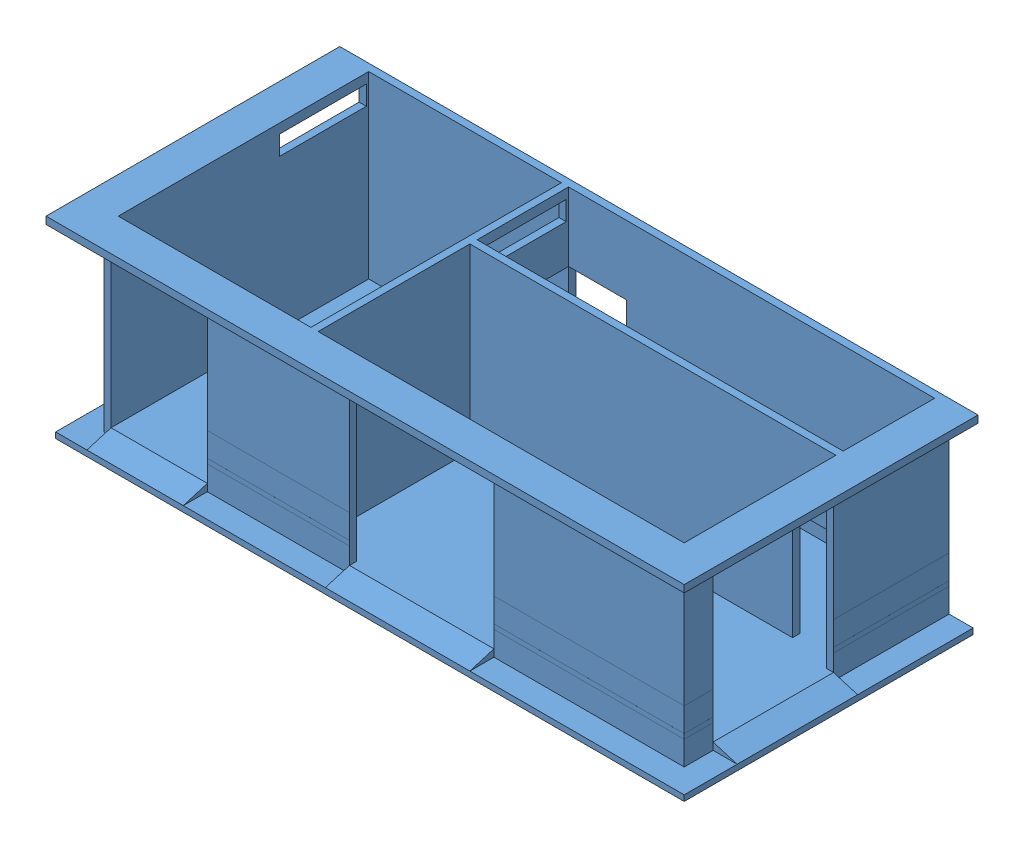
SolidWorks assembly Ensamblaje electricidad del cuarto, configuration Predeterminado. Lengths in mm.
Overall size (13250 4000 6100).
4 component instances, 4 part files, 9 mates.
Components (placement in the parent):
- Cuarto 3-10-18-1: Cuarto 3-10-18 [Predeterminado] at (9927.4307 8626.0275 5841.1732) size (13250 4000 6100)
- trafo de 50 kva-1: trafo de 50 kva [Predeterminado] at (6977.4307 6761.0275 7541.1732) x (1 0 0) z (0 1 0) size (900 600 801)
- tablero de distribuacion de 50 kva-1: tablero de distribuacion de 50 kva [Predeterminado] at (6377.4307 8661.0275 7391.1732) x (0 0 -1) z (-1 0 0) size (600 800 250)
- conexi trafo 50 kva-1: conexi trafo 50 kva [Predeterminado] at (6477.4307 7337.5055 7661.8509) x (0 0 -1) z (1 0 0) size (365.4 1012.7 313.7)
Mates (geometry in assembly coordinates):
- Coincidente1: coincident anti-aligned: plane of Cuarto 3-10-18-1 through (9927.4307 6761.0275 5841.1732) normal (0 1 0); plane of trafo de 50 kva-1 through (6977.4307 6761.0275 7541.1732) normal (0 -1 0)
- Distancia1: distance = 50 mm anti-aligned: plane of Cuarto 3-10-18-1 through (6127.4307 17612.5076 7891.1732) normal (0 0 -1); plane of trafo de 50 kva-1 through (6577.4307 7561.0275 7841.1732) normal (0 0 1)
- Coincidente3: coincident anti-aligned: plane of Cuarto 3-10-18-1 through (6127.4307 10011.0275 5991.1732) normal (1 0 0); plane of tablero de distribuacion de 50 kva-1 through (6127.4307 8661.0275 7391.1732) normal (-1 0 0)
- Distancia2: distance = 200 mm anti-aligned: plane of Cuarto 3-10-18-1 through (6127.4307 17612.5076 7891.1732) normal (0 0 -1); plane of tablero de distribuacion de 50 kva-1 through (6127.4307 9061.0275 7691.1732) normal (0 0 1)
- Distancia3: distance = 1500 mm anti-aligned: plane of Cuarto 3-10-18-1 through (9927.4307 6761.0275 5841.1732) normal (0 1 0); plane of tablero de distribuacion de 50 kva-1 through (6127.4307 8261.0275 7691.1732) normal (0 -1 0)
- Coincidente6: coincident anti-aligned: plane of trafo de 50 kva-1 through (6477.4307 6761.0275 7541.1732) normal (-1 0 0); plane of conexi trafo 50 kva-1 through (6477.4307 7337.5055 7661.8509) normal (1 0 0)
- Distancia4: distance = 450 mm anti-aligned: plane of Cuarto 3-10-18-1 through (6127.4307 10011.0275 5991.1732) normal (1 0 0); plane of trafo de 50 kva-1 through (6577.4307 7561.0275 7841.1732) normal (-1 0 0)
- Tangente1: tangent aligned: plane of trafo de 50 kva-1 through (6477.4307 7305.269 7674.5509) normal (0 0 1); cylinder of conexi trafo 50 kva-1 through (6477.4307 7337.5055 7661.8509) axis (-1 0 0) radius 12.7
- Distancia5: distance = 100 mm aligned: plane of trafo de 50 kva-1 through (6477.4307 7224.8055 7357.245) normal (0 -1 0); cylinder of conexi trafo 50 kva-1 through (6477.4307 7337.5055 7661.8509) axis (-1 0 0) radius 12.7
